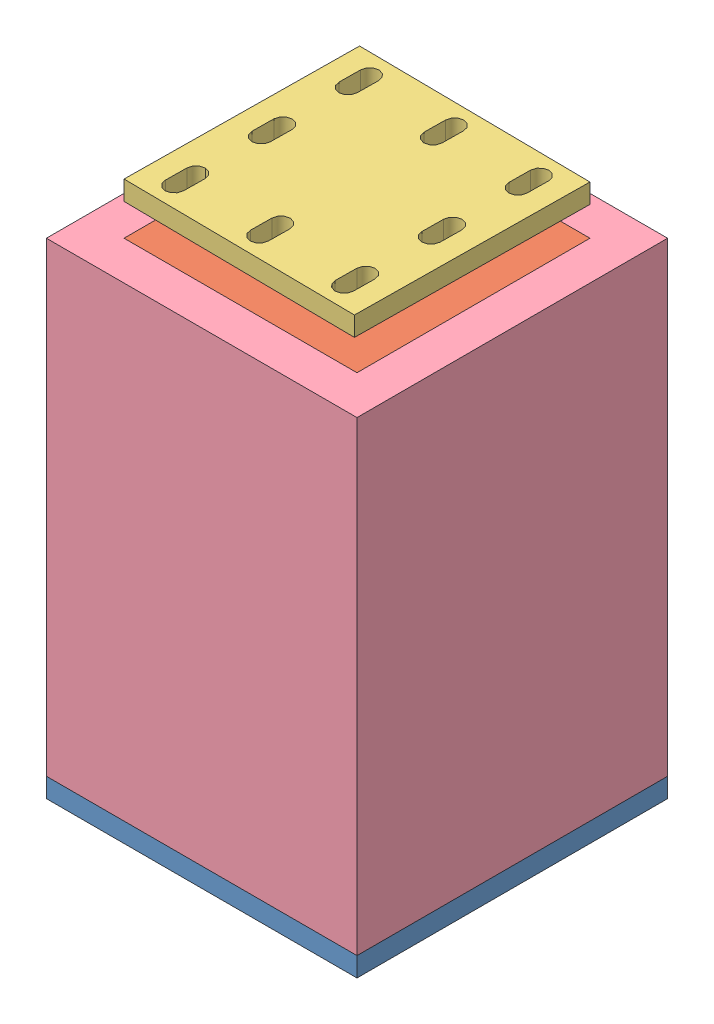
SolidWorks assembly Final_Payload, configuration Default. Lengths in mm.
Overall size (101.6 175.1 101.6).
4 component instances, 4 part files, 8 mates.
Components (placement in the parent):
- Housing Base-1: Housing Base [Default] at (43.937 32.3769 80.2107) size (101.6 25.4 101.6)
- Electronics Housing-1: Electronics Housing [Default] at (5.837 38.7269 118.3107) size (76.2 152.4 76.2)
- Camera Mounting Plate-1: Camera Mounting Plate [Default] at (43.937 201.1269 80.2107) x (0.999938 0 0.011099) z (-0.011099 0 0.999938) size (76.2 16.35 76.2)
- 6546K865_Multipurpose 6061 Aluminum Rectangular Tube-1: 6546K865_Multipurpose 6061 Aluminum Rectangular Tube [6546K865] at (43.937 114.9269 80.2107) x (1 0 0) z (0 -1 0) size (101.6 101.6 152.4)
Mates (geometry in assembly coordinates):
- Coincident1: coincident anti-aligned: plane of Housing Base-1 through (43.937 38.7269 80.2107) normal (0 1 0); plane of Electronics Housing-1 through (5.837 38.7269 42.1107) normal (0 -1 0)
- Coincident2: coincident anti-aligned: plane of Housing Base-1 through (43.937 57.7769 114.5007) normal (0 0 1); plane of Electronics Housing-1 through (9.647 187.3169 114.5007) normal (0 0 -1)
- Coincident3: coincident anti-aligned: plane of Housing Base-1 through (9.647 57.7769 80.2107) normal (-1 0 0); plane of Electronics Housing-1 through (9.647 187.3169 114.5007) normal (1 0 0)
- Coincident4: coincident anti-aligned: plane of Housing Base-1 through (43.937 38.7269 80.2107) normal (0 1 0); plane of 6546K865_Multipurpose 6061 Aluminum Rectangular Tube-1 through (43.937 38.7269 80.2107) normal (0 -1 0)
- Coincident5: coincident anti-aligned: plane of Electronics Housing-1 through (5.837 38.7269 42.1107) normal (-1 0 0); plane of 6546K865_Multipurpose 6061 Aluminum Rectangular Tube-1 through (5.837 38.7269 118.3107) normal (1 0 0)
- Coincident6: coincident anti-aligned: plane of Electronics Housing-1 through (5.837 38.7269 118.3107) normal (0 0 1); plane of 6546K865_Multipurpose 6061 Aluminum Rectangular Tube-1 through (82.037 38.7269 118.3107) normal (0 0 -1)
- Concentric1: concentric anti-aligned: circle of Electronics Housing-1; circle of Camera Mounting Plate-1
- Coincident7: coincident anti-aligned: plane of Electronics Housing-1 through (5.837 191.1269 42.1107) normal (0 1 0); plane of Camera Mounting Plate-1 through (43.937 191.1269 80.2107) normal (0 -1 0)
